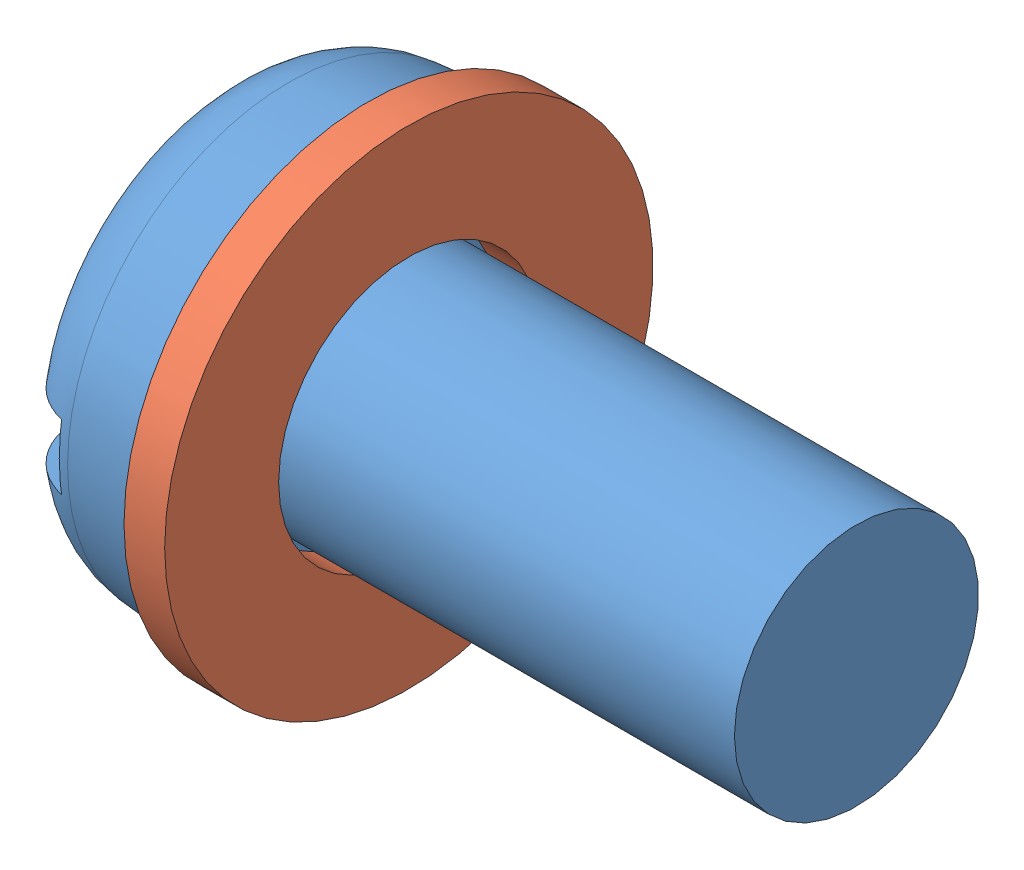
SolidWorks assembly Assemblage1, configuration Défaut. Lengths in mm.
Overall size (7.8 6 6).
2 component instances, 2 part files, 2 mates.
Components (placement in the parent):
- slotted pan head screw_iso-1: slotted pan head screw_iso [ISO 1580 - M3 x 6 - 6N] at (-24.3859 -1.1067 0) size (7.8 5.6 5.6)
- plain washer small grade a_iso-1: plain washer small grade a_iso [Washer ISO 7092 - 3] at (-22.0859 -1.1067 0) size (0.5 6 6)
Mates (geometry in assembly coordinates):
- Coaxiale1: concentric: cylinder of assembly; circle of assembly; cylinder of slotted pan head screw_iso-1 through (-49.7859 -1.1067 0) axis (-1 0 0) radius 1.5; circle of plain washer small grade a_iso-1
- Coïncidente1: coincident: plane of assembly; plane of assembly; plane of slotted pan head screw_iso-1 through (-22.5859 0.3933 0) normal (1 0 0); plane of plain washer small grade a_iso-1 through (-22.5859 1.8933 0) normal (-1 0 0)
